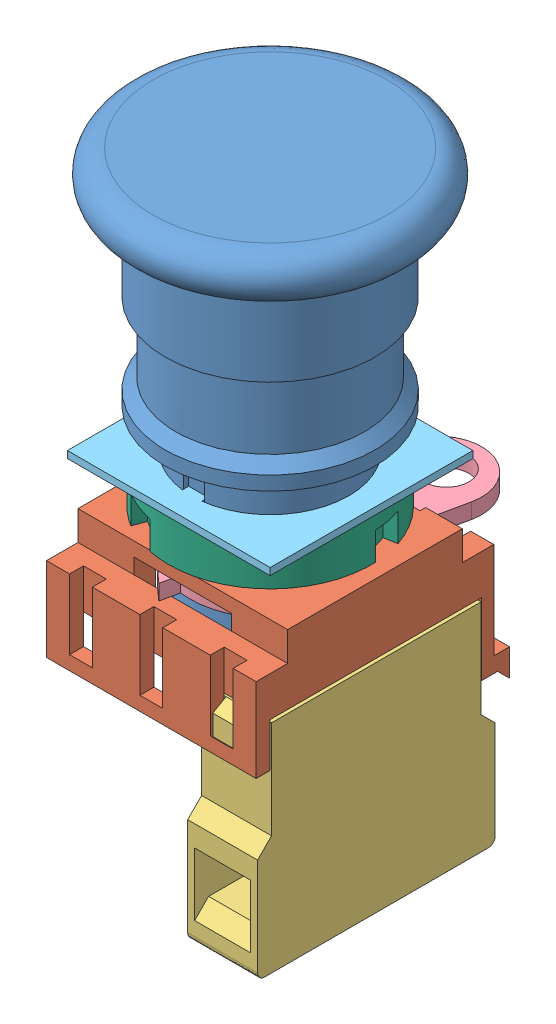
SolidWorks assembly Omron-A22EL-M-24A-01, configuration Default. Lengths in mm.
Overall size (40 87.2 48.31).
6 component instances, 6 part files, 13 mates.
Components (placement in the parent):
- Operation Unit^Omron-A22EL-M-24A-01-1: Operation Unit^Omron-A22EL-M-24A-01 [Default] at origin size (40 54.5 40) (virtual)
- Mounting Latches^Omron-A22EL-M-24A-01-1: Mounting Latches^Omron-A22EL-M-24A-01 [Default] at (0 -14 0) x (0 0 -1) z (1 0 0) size (36.25 21.9 30) (virtual)
- A22-01^Omron-A22EL-M-24A-01-1: A22-01^Omron-A22EL-M-24A-01 [Default] at (10.2 -24.2 0) x (0 0 1) z (-1 0 0) size (34 36.5 10) (virtual)
- Locking ring^Omron-A22EL-M-24A-01-1: Locking ring^Omron-A22EL-M-24A-01 [Default] at (0 -16 0) x (0.207912 0 -0.978148) z (-0.978148 0 -0.207912) size (40.58 2.2 23) (virtual)
- Washer^Omron-A22EL-M-24A-01-1: Washer^Omron-A22EL-M-24A-01 [Default] at (0 -6.5575 0) x (1 0 0) z (0 1 0) size (29 29 1) (virtual)
- Nut^Omron-A22EL-M-24A-01-1: Nut^Omron-A22EL-M-24A-01 [Default] at (0 -6.5575 0) x (0.940673 0 0.339315) z (0 -1 0) size (29 29 5.9) (virtual)
Mates (geometry in assembly coordinates):
- Concentric1: concentric aligned: cylinder of Mounting Latches^Omron-A22EL-M-24A-01-1 through (0 -23.901 0) axis (0 1 0) radius 10; cylinder of Locking ring^Omron-A22EL-M-24A-01-1 through (0 -18.2 0) axis (0 1 0) radius 10
- Coincident2: coincident anti-aligned: plane of Mounting Latches^Omron-A22EL-M-24A-01-1 through (0 -16 0) normal (0 -1 0); plane of Locking ring^Omron-A22EL-M-24A-01-1 through (0 -16 0) normal (0 1 0)
- LimitAngle3: limit planar angle = 3.351032 rad anti-aligned: plane of Locking ring^Omron-A22EL-M-24A-01-1 through (8.1205 -18.2 -8.143) normal (0.978148 0 0.207912); plane of Mounting Latches^Omron-A22EL-M-24A-01-1 through (15 -23.9 12.5) normal (1 0 0)
- Coincident5: coincident anti-aligned: plane of Operation Unit^Omron-A22EL-M-24A-01-1 through (0 -14 0) normal (0 -1 0); plane of Mounting Latches^Omron-A22EL-M-24A-01-1 through (0 -14 0) normal (0 1 0)
- Concentric3: concentric aligned: cylinder of Operation Unit^Omron-A22EL-M-24A-01-1 through (0 -22.5 0) axis (0 1 0) radius 10; cylinder of Mounting Latches^Omron-A22EL-M-24A-01-1 through (0 -23.901 0) axis (0 1 0) radius 10
- Coincident7: coincident anti-aligned: plane of Mounting Latches^Omron-A22EL-M-24A-01-1 through (8.4333 -28.2 4.48) normal (0 1 0); plane of A22-01^Omron-A22EL-M-24A-01-1 through (8.7 -28.2 16.9) normal (0 -1 0)
- Coincident8: coincident anti-aligned: plane of Mounting Latches^Omron-A22EL-M-24A-01-1 through (11.7 -18.2 4.48) normal (-1 0 0); plane of A22-01^Omron-A22EL-M-24A-01-1 through (11.7 -24.2 0) normal (1 0 0)
- Coincident9: coincident anti-aligned: plane of Mounting Latches^Omron-A22EL-M-24A-01-1 through (-15 -30.2 15) normal (0 0 -1); plane of A22-01^Omron-A22EL-M-24A-01-1 through (5.2 -24.2 15) normal (0 0 1)
- Concentric4: concentric anti-aligned: cylinder of Operation Unit^Omron-A22EL-M-24A-01-1 through (0 -14 0) axis (0 1 0) radius 11; cylinder of Washer^Omron-A22EL-M-24A-01-1 through (0 -5.5565 0) axis (0 -1 0) radius 11.25
- Parallel3: parallel anti-aligned: plane of Operation Unit^Omron-A22EL-M-24A-01-1 through (1.5 -22.5 -10.15) normal (-1 0 0); plane of Washer^Omron-A22EL-M-24A-01-1 through (1.4 -5.5565 -10.25) normal (1 0 0)
- Coincident11: coincident anti-aligned: plane of Washer^Omron-A22EL-M-24A-01-1 through (0 -6.5575 0) normal (0 -1 0); plane of Nut^Omron-A22EL-M-24A-01-1 through (0 -6.5575 0) normal (0 1 0)
- Concentric5: concentric aligned: cylinder of Operation Unit^Omron-A22EL-M-24A-01-1 through (0 -14 0) axis (0 1 0) radius 11; cylinder of Nut^Omron-A22EL-M-24A-01-1 through (0 -12.4575 0) axis (0 1 0) radius 10.7
- LimitDistance1: limit distance = 1.5425 mm anti-aligned: plane of Nut^Omron-A22EL-M-24A-01-1 through (0 -12.4575 0) normal (0 -1 0); plane of Mounting Latches^Omron-A22EL-M-24A-01-1 through (0 -14 0) normal (0 1 0)
